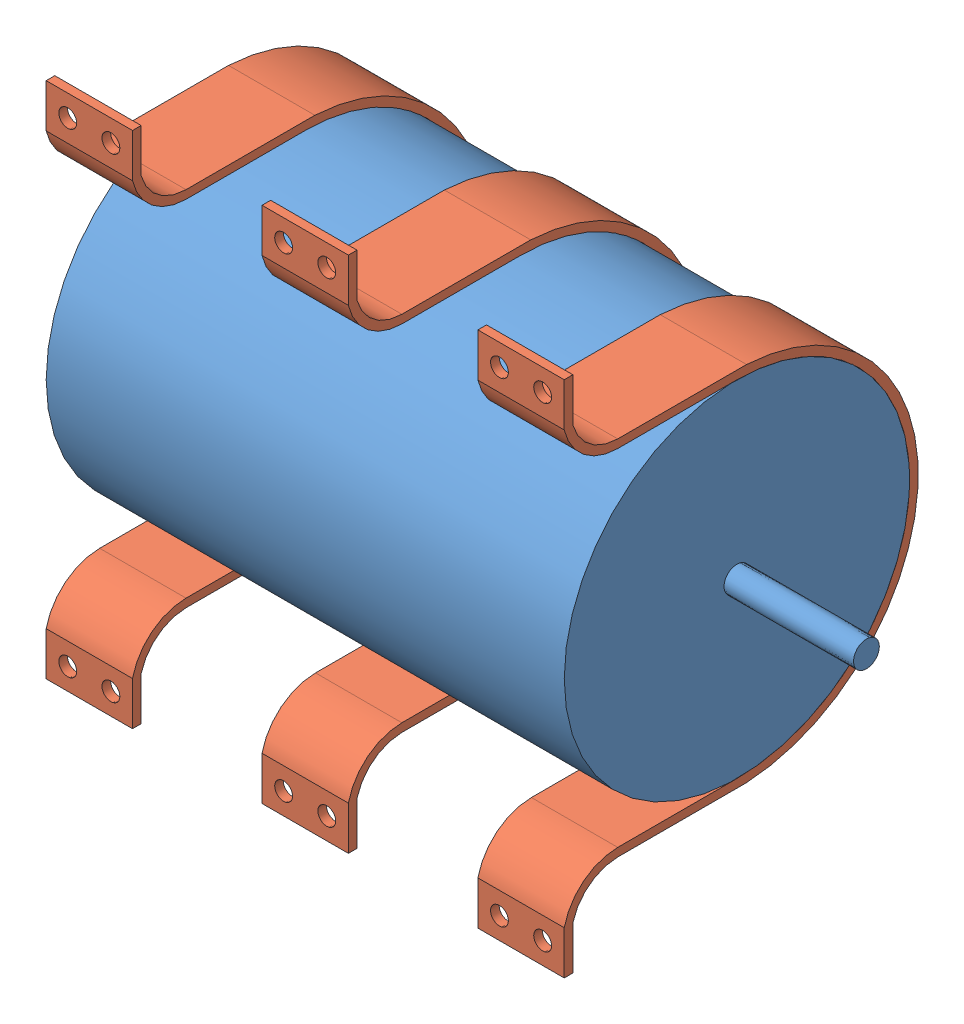
SolidWorks assembly moteur-fixation, configuration Défaut. Lengths in mm.
Overall size (75 60.01 41).
4 component instances, 2 part files, 6 mates.
Components (placement in the parent):
- moteur40-60-1: moteur40-60 [Défaut] at (-38.9333 4.3561 110) size (75 40 40)
- fixationMoteur40-2-2: fixationMoteur40-2 [Défaut] at (21.0667 4.3561 110) x (0 1 0) z (0 0 1) size (60.01 10 41)
- fixationMoteur40-2-3: fixationMoteur40-2 [Défaut] at (-3.9333 4.3561 110) x (0 1 0) z (0 0 1) size (60.01 10 41)
- fixationMoteur40-2-4: fixationMoteur40-2 [Défaut] at (-28.9333 4.3561 110) x (0 1 0) z (0 0 1) size (60.01 10 41)
Mates (geometry in assembly coordinates):
- Coaxiale1: concentric anti-aligned: cylinder of moteur40-60-1 through (21.0667 4.3561 110) axis (-1 0 0) radius 20; cylinder of fixationMoteur40-2-2 through (11.0667 4.3561 110) axis (1 0 0) radius 20
- Coïncidente2: coincident anti-aligned: plane of moteur40-60-1 through (21.0667 4.3561 110) normal (1 0 0); circle of fixationMoteur40-2-2
- Coaxiale3: concentric anti-aligned: cylinder of moteur40-60-1 through (21.0667 4.3561 110) axis (-1 0 0) radius 20; cylinder of fixationMoteur40-2-3 through (-13.9333 4.3561 110) axis (1 0 0) radius 20
- Distance2: distance = 15 mm anti-aligned: plane of fixationMoteur40-2-3 through (-3.9333 -22.0336 123.7714) normal (1 0 0); plane of fixationMoteur40-2-2 through (11.0667 -22.0336 123.7714) normal (-1 0 0)
- Coaxiale5: concentric anti-aligned: cylinder of moteur40-60-1 through (21.0667 4.3561 110) axis (-1 0 0) radius 20; cylinder of fixationMoteur40-2-4 through (-38.9333 4.3561 110) axis (1 0 0) radius 20
- Coïncidente5: coincident aligned: plane of moteur40-60-1 through (-38.9333 4.3561 110) normal (-1 0 0); plane of fixationMoteur40-2-4 through (-38.9333 -22.0336 123.7714) normal (-1 0 0)
